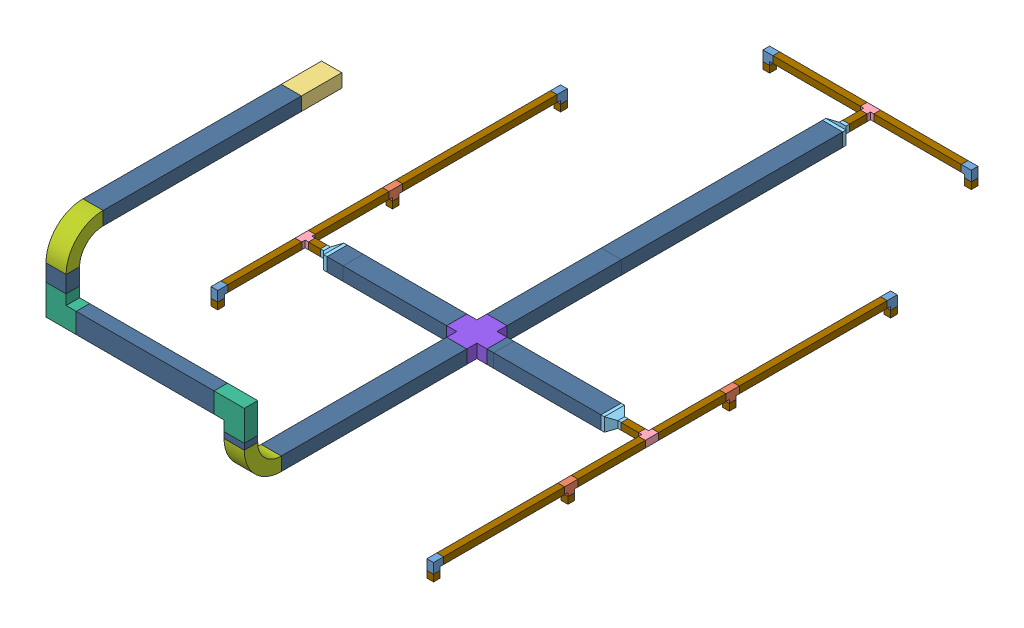
SolidWorks assembly HVAC Ducting9-Assem2, configuration Default. Lengths in mm.
Overall size (27217.31 10697 48008.69).
53 component instances, 10 part files, 10 mates.
Components (placement in the parent):
- hvac vertical corner-1: hvac vertical corner [Vertical Corner 0.5 x 0.5 x 0.5 x 0.5] at (7500 12250 -23126) x (-1 0 0) z (0 0 -1) size (760 760 500)
- hvac vertical corner-2: hvac vertical corner [Vertical Corner 0.5 x 0.5 x 0.5 x 0.5] at (-7500 12250 -23126) size (760 760 500)
- hvac vertical corner-3: hvac vertical corner [Vertical Corner 0.5 x 0.5 x 0.5 x 0.5] at (-12776 12250 -12850) x (0 0 1) z (-1 0 0) size (760 760 500)
- hvac vertical corner-4: hvac vertical corner [Vertical Corner 0.5 x 0.5 x 0.5 x 0.5] at (-12776 12250 12650) x (0 0 -1) z (1 0 0) size (760 760 500)
- hvac vertical tee-1: hvac vertical tee [Vertical Tee 0.5 x 0.5 x 0.5 x 0.5] at (-12776 12250 -350) x (0 0 1) z (-1 0 0) size (1020 760 500)
- hvac vertical corner-5: hvac vertical corner [Vertical Corner 0.5 x 0.5 x 0.5 x 0.5] at (12775 12250 -11850) x (0 0 1) z (-1 0 0) size (760 760 500)
- hvac vertical corner-6: hvac vertical corner [Vertical Corner 0.5 x 0.5 x 0.5 x 0.5] at (12775 12250 22150) x (0 0 -1) z (1 0 0) size (760 760 500)
- hvac vertical tee-2: hvac vertical tee [Vertical Tee 0.5 x 0.5 x 0.5 x 0.5] at (12775 12250 150) x (0 0 1) z (-1 0 0) size (1020 760 500)
- hvac vertical tee-3: hvac vertical tee [Vertical Tee 0.5 x 0.5 x 0.5 x 0.5] at (12775 12250 12150) x (0 0 -1) z (1 0 0) size (1020 760 500)
- hvac duct-1: hvac duct [Rectangular Duct 1.5 x 1.0 x 0.002] at (-13250 21447 6700) x (-1 0 0) z (0 0 -1) size (1500 1000 3010)
- hvac tee-1: hvac tee [Tee 0.5 x 0.5 x 0.5 x 0.5] at (0 12250 -23126) size (1020 500 760)
- hvac tee-2: hvac tee [Tee 0.5 x 0.5 x 0.5 x 0.5] at (-12776 12250 6150) x (0 0 -1) z (1 0 0) size (1020 500 760)
- hvac tee-3: hvac tee [Tee 0.5 x 0.5 x 0.5 x 0.5] at (12775 12250 6150) x (0 0 1) z (-1 0 0) size (1020 500 760)
- hvac reducer s-2: hvac reducer s [Reducer 1.5x1.0 to 0.5x0.5] at (0 12250 -20559.5909) size (1500 1000 1020)
- hvac corner-1: hvac corner [Corner 1.5 x 1.0 x 1.5 x 1.0] at (-13250 16447 23700) x (0 1 0) z (0.980581 0 0.196116) size (2260 1421.84 2402.42)
- hvac corner-2: hvac corner [Corner 1.5 x 1.0 x 1.5 x 1.0] at (0 16447 23700) x (-1 0 0) z (0 -0.980581 -0.196116) size (2260 1421.84 2402.42)
- hvac 90deg bend-1: hvac 90deg bend [Vertical Bend 1.5 x 1.0 x 0.002 at 90 Deg] at (-13250 19197 21450) x (0 0 -1) z (0 -1 0) size (2760 1500 2760)
- hvac 90deg bend-2: hvac 90deg bend [Vertical Bend 1.5 x 1.0 x 0.002 at 90 Deg] at (0 14500 21450) x (0 0 -1) z (0 1 0) size (2760 1500 2760)
- hvac reducer s-3: hvac reducer s [Reducer 1.5x1.0 to 0.5x0.5] at (-10643.4007 12250 6150) x (0 0 -1) z (1 0 0) size (1500 1000 1020)
- hvac reducer s-4: hvac reducer s [Reducer 1.5x1.0 to 0.5x0.5] at (10235.8015 12250 6150) x (0 0 1) z (-1 0 0) size (1500 1000 1020)
- hvac cross-1: hvac cross [Cross 1.5 x 1.0 x 1.5 x 1.0] at (0 12250 6150) x (0 0 1) z (-1 0 0) size (3020 1000 3020)
- RoundDuct05x05x0002-1: RoundDuct05x05x0002 [Rectangular Duct 0.5 x 0.5 x 0.002, 1] at (500 12250 -23126) x (0 0 -1) z (1 0 0) size (500 500 6510)
- RoundDuct05x05x0002-2: RoundDuct05x05x0002 [Rectangular Duct 0.5 x 0.5 x 0.002, 1] at (-500 12250 -23126) x (0 0 1) z (-1 0 0) size (500 500 6510)
- RoundDuct05x05x0002-3: RoundDuct05x05x0002 [Rectangular Duct 0.5 x 0.5 x 0.002, 2] at (7500 11750 -23126) x (0 0 1) z (0 -1 0) size (500 500 510)
- RoundDuct05x05x0002-4: RoundDuct05x05x0002 [Rectangular Duct 0.5 x 0.5 x 0.002, 2] at (-7500 11750 -23126) x (0 0 -1) z (0 -1 0) size (500 500 510)
- RoundDuct05x05x0002-5: RoundDuct05x05x0002 [Rectangular Duct 0.5 x 0.5 x 0.002, 3] at (-12776 12250 6650) size (500 500 5510)
- RoundDuct05x05x0002-6: RoundDuct05x05x0002 [Rectangular Duct 0.5 x 0.5 x 0.002, 3] at (-12776 12250 5650) x (-1 0 0) z (0 0 -1) size (500 500 5510)
- RoundDuct05x05x0002-7: RoundDuct05x05x0002 [Rectangular Duct 0.5 x 0.5 x 0.002, 2] at (-12776 11750 -12850) x (1 0 0) z (0 -1 0) size (500 500 510)
- RoundDuct05x05x0002-8: RoundDuct05x05x0002 [Rectangular Duct 0.5 x 0.5 x 0.002, 2] at (-12776 11750 12650) x (-1 0 0) z (0 -1 0) size (500 500 510)
- RoundDuct05x05x0002-9: RoundDuct05x05x0002 [Rectangular Duct 0.5 x 0.5 x 0.002, 4] at (-12776 12250 -850) x (-1 0 0) z (0 0 -1) size (500 500 11510)
- RoundDuct05x05x0002-10: RoundDuct05x05x0002 [Rectangular Duct 0.5 x 0.5 x 0.002, 2] at (-12776 11750 -350) x (1 0 0) z (0 -1 0) size (500 500 510)
- RoundDuct05x05x0002-11: RoundDuct05x05x0002 [Rectangular Duct 0.5 x 0.5 x 0.002, 5] at (12775 12250 5650) x (-1 0 0) z (0 0 -1) size (500 500 5010)
- RoundDuct05x05x0002-12: RoundDuct05x05x0002 [Rectangular Duct 0.5 x 0.5 x 0.002, 5] at (12775 12250 6650) size (500 500 5010)
- RoundDuct05x05x0002-13: RoundDuct05x05x0002 [Rectangular Duct 0.5 x 0.5 x 0.002, 6] at (12775 12250 -350) x (-1 0 0) z (0 0 -1) size (500 500 11010)
- RoundDuct05x05x0002-14: RoundDuct05x05x0002 [Rectangular Duct 0.5 x 0.5 x 0.002, 2] at (12775 11750 -11850) x (1 0 0) z (0 -1 0) size (500 500 510)
- RoundDuct05x05x0002-15: RoundDuct05x05x0002 [Rectangular Duct 0.5 x 0.5 x 0.002, 2] at (12775 11750 22150) x (-1 0 0) z (0 -1 0) size (500 500 510)
- RoundDuct05x05x0002-16: RoundDuct05x05x0002 [Rectangular Duct 0.5 x 0.5 x 0.002, 2] at (12775 11750 150) x (1 0 0) z (0 -1 0) size (500 500 510)
- RoundDuct05x05x0002-17: RoundDuct05x05x0002 [Rectangular Duct 0.5 x 0.5 x 0.002, 7] at (12775 12250 12650) size (500 500 9010)
- RoundDuct05x05x0002-18: RoundDuct05x05x0002 [Rectangular Duct 0.5 x 0.5 x 0.002, 2] at (12775 11750 12150) x (-1 0 0) z (0 -1 0) size (500 500 510)
- RoundDuct05x05x0002-24: RoundDuct05x05x0002 [Rectangular Duct 0.5 x 0.5 x 0.002, 8] at (0 12250 -22626) size (500 500 1326.41)
- RectangularDuct15x10x0002^HVAC Ducting9-Assem2-1: RectangularDuct15x10x0002^HVAC Ducting9-Assem2 [Rectangular Duct 1.5 x 1.0 x 0.002, 1] at (0 12250 -20309.5909) size (1500 1000 16465.59) (virtual)
- RectangularDuct15x10x0002^HVAC Ducting9-Assem2-2: RectangularDuct15x10x0002^HVAC Ducting9-Assem2 [Rectangular Duct 1.5 x 1.0 x 0.002, 2] at (-13250 21447 6700) size (1500 1000 14760) (virtual)
- RectangularDuct15x10x0002^HVAC Ducting9-Assem2-3: RectangularDuct15x10x0002^HVAC Ducting9-Assem2 [Rectangular Duct 1.5 x 1.0 x 0.002, 3] at (-13250 19197 23700) x (1 0 0) z (0 -1 0) size (1500 1000 1260) (virtual)
- RectangularDuct15x10x0002^HVAC Ducting9-Assem2-4: RectangularDuct15x10x0002^HVAC Ducting9-Assem2 [Rectangular Duct 1.5 x 1.0 x 0.002, 4] at (-11750 16447 23700) x (0 1 0) z (1 0 0) size (1500 1000 10260) (virtual)
- RectangularDuct15x10x0002^HVAC Ducting9-Assem2-5: RectangularDuct15x10x0002^HVAC Ducting9-Assem2 [Rectangular Duct 1.5 x 1.0 x 0.002, 5] at (0 14947 23700) x (-1 0 0) z (0 -1 0) size (1500 1000 457) (virtual)
- RectangularDuct15x10x0002^HVAC Ducting9-Assem2-6: RectangularDuct15x10x0002^HVAC Ducting9-Assem2 [Rectangular Duct 1.5 x 1.0 x 0.002, 7] at (0 12250 21450) x (1 0 0) z (0 0 -1) size (1500 1000 13810) (virtual)
- RoundDuct05x05x0002-25: RoundDuct05x05x0002 [Rectangular Duct 0.5 x 0.5 x 0.002, 9] at (-12276 12250 6150) x (0 0 -1) z (1 0 0) size (500 500 892.6)
- RectangularDuct15x10x0002^HVAC Ducting9-Assem2-7: RectangularDuct15x10x0002^HVAC Ducting9-Assem2 [Rectangular Duct 1.5 x 1.0 x 0.002, 8] at (-10393.4007 12250 6150) x (0 0 -1) z (1 0 0) size (1500 1000 1197.77) (virtual)
- RoundDuct05x05x0002-26: RoundDuct05x05x0002 [Rectangular Duct 0.5 x 0.5 x 0.002, 10] at (12275 12250 6150) x (0 0 1) z (-1 0 0) size (500 500 1299.2)
- RectangularDuct15x10x0002^HVAC Ducting9-Assem2-8: RectangularDuct15x10x0002^HVAC Ducting9-Assem2 [Rectangular Duct 1.5 x 1.0 x 0.002, 9] at (9985.8015 12250 6150) x (0 0 1) z (-1 0 0) size (1500 1000 7995.8) (virtual)
- RectangularDuct15x10x0002^HVAC Ducting9-Assem2-9: RectangularDuct15x10x0002^HVAC Ducting9-Assem2 [Rectangular Duct 1.5 x 1.0 x 0.002, 10] at (0 12250 4650) x (1 0 0) z (0 0 -1) size (1500 1000 8514.01) (virtual)
- RectangularDuct15x10x0002^HVAC Ducting9-Assem2-10: RectangularDuct15x10x0002^HVAC Ducting9-Assem2 [Rectangular Duct 1.5 x 1.0 x 0.002, 11] at (1500 12250 6150) x (0 0 -1) z (1 0 0) size (1500 1000 510) (virtual)
- RectangularDuct15x10x0002^HVAC Ducting9-Assem2-11: RectangularDuct15x10x0002^HVAC Ducting9-Assem2 [Rectangular Duct 1.5 x 1.0 x 0.002, 12] at (-1500 12250 6150) x (0 0 1) z (-1 0 0) size (1500 1000 7715.63) (virtual)
Mates (geometry in assembly coordinates):
- ProfileCenter1: profile center anti-aligned: plane of Part1^Assem2-1 through (-15500 23147 3700) normal (0 0 1); plane of hvac duct-1 through (-13250 21447 3700) normal (0 0 -1)
- Coincident1: coincident aligned: plane of hvac tee-1 through (500 12000 -22876) normal (0 -1 0); plane of hvac tee-3 through (12525 12000 6650) normal (0 -1 0)
- Distance1: distance = 12000 mm anti-aligned: plane of hvac tee-1 through (500 12000 -22876) normal (0 -1 0); plane of Building-1 through (0 0 0) normal (0 1 0)
- Width1: width aligned: plane of Building-1 through (-17500 10000 -28000) normal (1 0 0); plane of hvac tee-1 through (17500 10000 -28000) normal (-1 0 0); plane of Building-1 through (500 12250 -23126) normal (1 0 0); plane of hvac tee-1 through (-500 12250 -23126) normal (-1 0 0)
- Width2: width aligned: plane of Building-1 through (-17500 10000 -28000) normal (0 0 1); plane of hvac tee-1 through (-17500 10000 -18000) normal (0 0 -1); plane of Building-1 through (0 12250 -22626) normal (0 0 1); plane of hvac tee-1 through (500 12500 -23374) normal (0 0 1)
- Coincident2: coincident aligned: plane of hvac tee-2 through (-12526 12000 5650) normal (0 -1 0); plane of hvac tee-3 through (12525 12000 6650) normal (0 -1 0)
- Width3: width aligned: plane of Building-1 through (-17500 10000 6000) normal (0 0 -1); plane of hvac tee-2 through (-17500 10000 6300) normal (0 0 1); plane of Building-1 through (-12776 12250 5650) normal (0 0 -1); plane of hvac tee-2 through (-12776 12250 6650) normal (0 0 1)
- Width4: width anti-aligned: plane of Building-1 through (-7800 10000 -18000) normal (-1 0 0); plane of hvac tee-2 through (-17500 10000 -28000) normal (1 0 0); plane of Building-1 through (-12276 12250 6150) normal (1 0 0); plane of hvac tee-2 through (-13024 12500 5650) normal (1 0 0)
- Width5: width anti-aligned: plane of Building-1 through (7500 10000 6300) normal (0 0 1); plane of hvac tee-3 through (7500 10000 6000) normal (0 0 -1); plane of Building-1 through (12775 12250 5650) normal (0 0 -1); plane of hvac tee-3 through (12775 12250 6650) normal (0 0 1)
- Width6: width anti-aligned: plane of Building-1 through (17500 10000 -28000) normal (-1 0 0); plane of hvac tee-3 through (7800 10000 -18000) normal (1 0 0); plane of Building-1 through (13025 12500 6650) normal (1 0 0); plane of hvac tee-3 through (12275 12250 6150) normal (-1 0 0)
